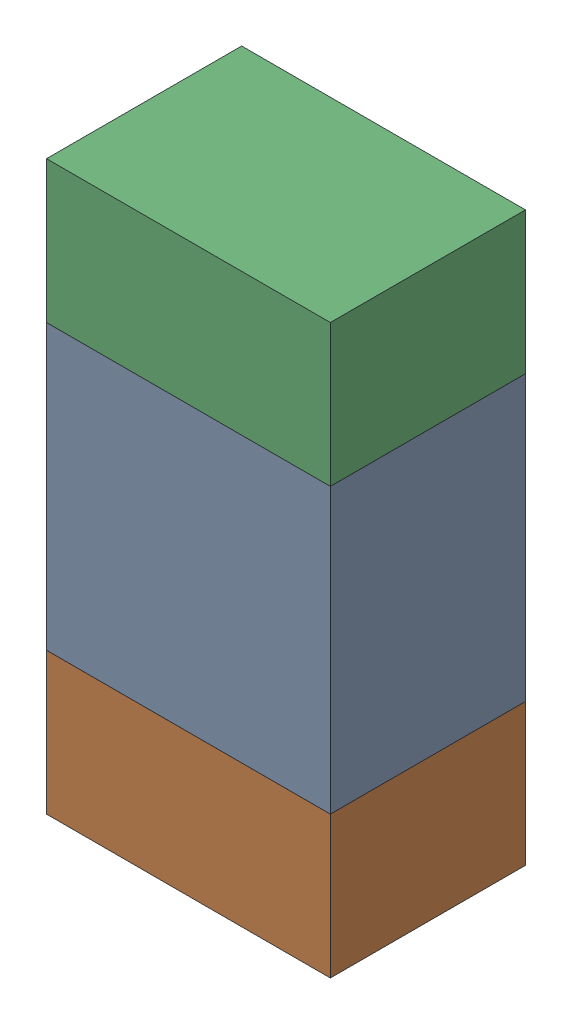
SolidWorks assembly R48, configuration ﾃﾞﾌｫﾙﾄ. Lengths in mm.
Overall size (0.8 1.6 0.55).
6 component instances, 2 part files, 0 mates.
Components (placement in the parent):
- 689261648-1: 689261648 [ﾃﾞﾌｫﾙﾄ] at (64.9999 35.75 -1.7503) size (0.8 0.8 0.55)
  - Extruded_33-1: Extruded_33 [ﾃﾞﾌｫﾙﾄ] at origin size (0.8 0.8 0.55)
- 689261784-1: 689261784 [ﾃﾞﾌｫﾙﾄ] at (64.9999 35.1499 -1.7503) size (0.8 0.4 0.55)
  - Extruded_34-1: Extruded_34 [ﾃﾞﾌｫﾙﾄ] at origin size (0.8 0.4 0.55)
- 689261784-2: 689261784 [ﾃﾞﾌｫﾙﾄ] at (64.9999 36.3499 -1.7503) size (0.8 0.4 0.55)
  - Extruded_34-1: Extruded_34 [ﾃﾞﾌｫﾙﾄ] at origin size (0.8 0.4 0.55)
